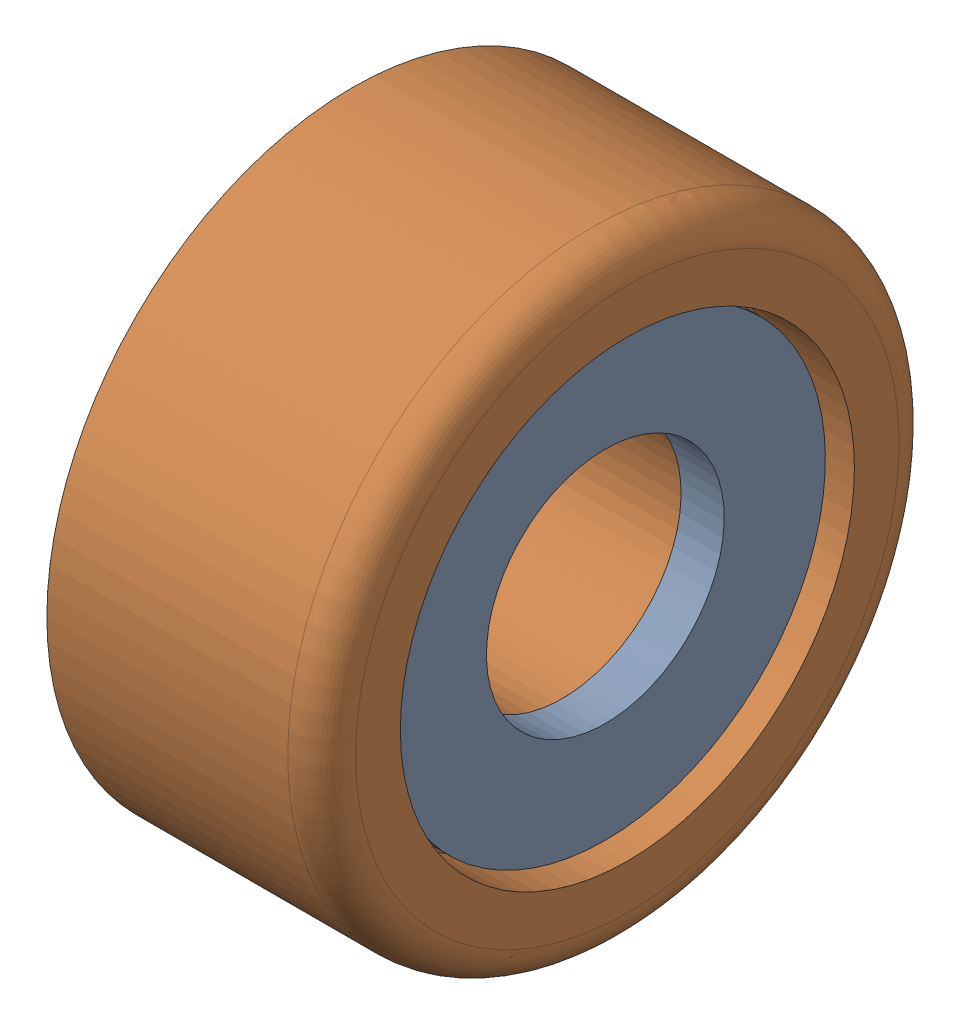
SolidWorks assembly 3,5 mm (Video Red), configuration Default. Lengths in mm.
Overall size (4.05 9 9).
2 component instances, 2 part files, 0 mates.
Components (placement in the parent):
- Part216_3-1: Part216_3 [Default] at (32.1699 -0.8638 41.0298) x (0 1 0) z (1 0 0) size (6.48 6.48 0.63)
- Part215_3-1: Part215_3 [Default] at (29.0831 -0.8638 41.0298) x (0 1 0) z (1 0 0) size (9 9 4.05)
